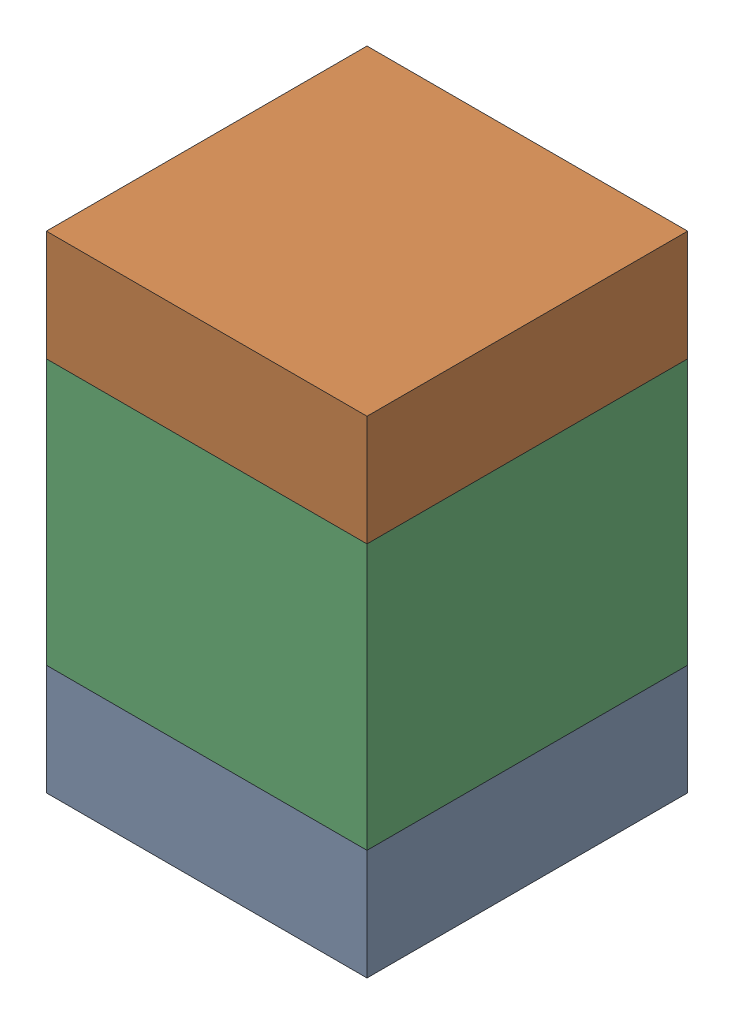
SolidWorks assembly C128_1PCB, configuration Default. Lengths in mm.
Overall size (1.45 2.2 1.45).
6 component instances, 2 part files, 0 mates.
Components (placement in the parent):
- 846485056-1: 846485056 [Default] at (104.1 121.05 0) size (1.45 0.5 1.45)
  - Extruded_39-1: Extruded_39 [Default] at origin size (1.45 0.5 1.45)
- 846485056-2: 846485056 [Default] at (104.1 122.75 0) size (1.45 0.5 1.45)
  - Extruded_39-1: Extruded_39 [Default] at origin size (1.45 0.5 1.45)
- 846485192-1: 846485192 [Default] at (104.1 121.9 0) size (1.45 1.2 1.45)
  - Extruded_40-1: Extruded_40 [Default] at origin size (1.45 1.2 1.45)
